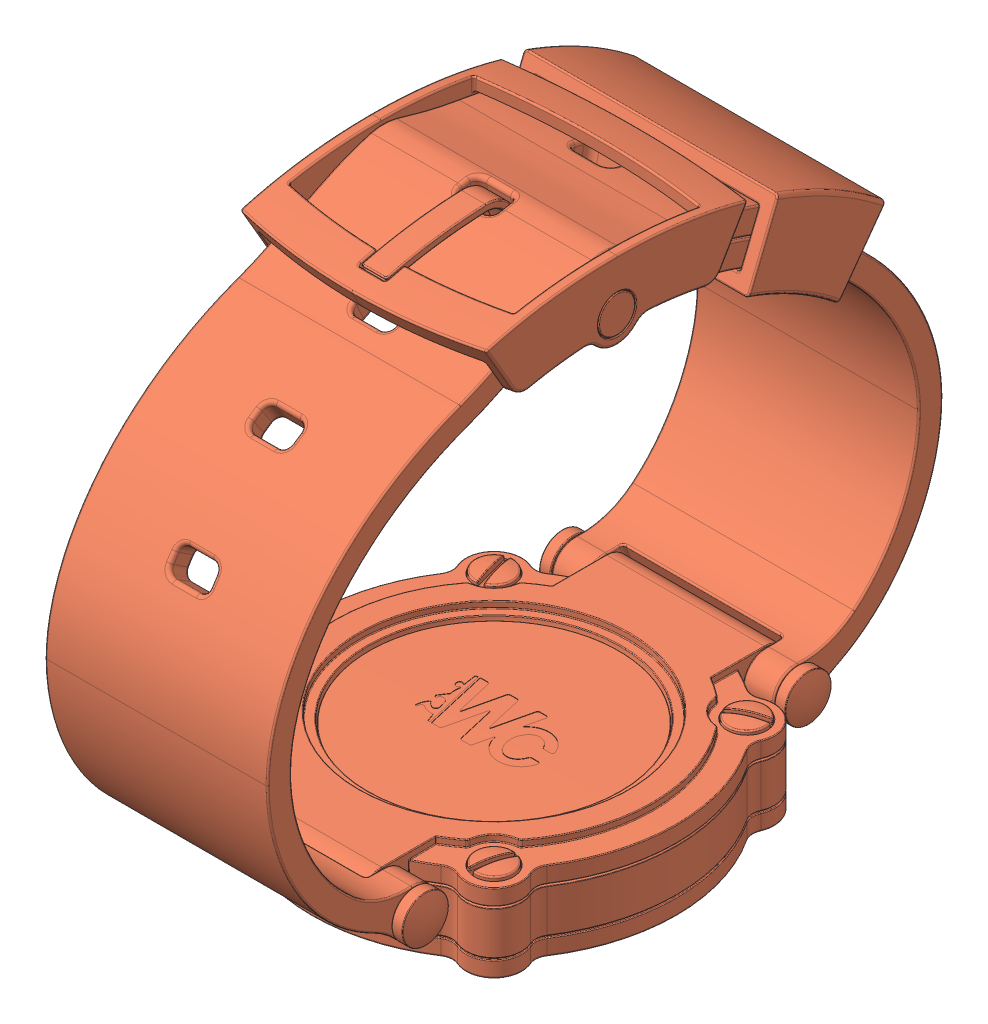
SolidWorks assembly RISE-watch_assembled_X3, configuration Default. Lengths in mm.
Overall size (49.3 71.5 90.18).
2 component instances, 2 part files, 3 mates.
Components (placement in the parent):
- mech-X14-1: mech-X14 [Default] at (-2.3352 2.8757 -0.7215) size (36.7 5.15 36)
- RISE02-watch_X1-1: RISE02-watch_X1 [Default] at (-2.3352 -2.9243 -0.7215) x (-1 0 0) z (0 0 1) size (49.3 71.5 90.18)
Mates (geometry in assembly coordinates):
- Coincident2: coincident aligned: plane of mech-X14-1 through (-2.3352 2.8757 -0.7215) normal (0 0 1); plane of RISE02-watch_X1-1 through (-2.3352 -2.9243 -0.7215) normal (0 0 1)
- Coincident3: coincident anti-aligned: plane of mech-X14-1 through (-2.3352 2.8757 -0.7215) normal (1 0 0); plane of RISE02-watch_X1-1
- Distance1: distance = 0.1 mm anti-aligned: plane of RISE02-watch_X1-1 through (-2.3352 -0.3743 -0.7215) normal (0 1 0); plane of mech-X14-1 through (2.0695 -0.2743 2.9746) normal (0 -1 0)
